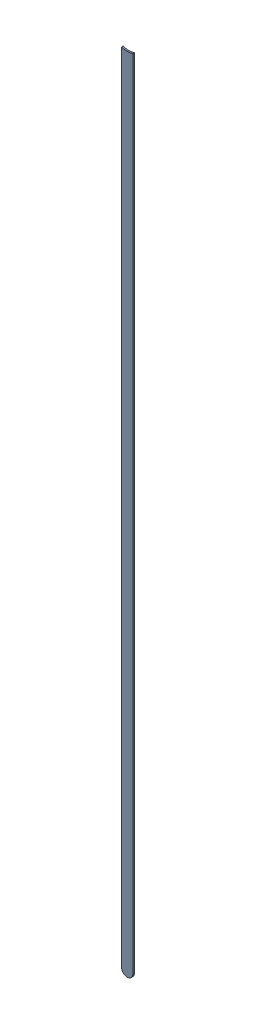
SolidWorks assembly Track (20.3mm,11.119mm)(20.3mm,29.4mm) on Bottom Layer, configuration Predeterminado. Lengths in mm.
Overall size (0.25 18.08 0.04).
2 component instances, 1 part files, 0 mates.
Components (placement in the parent):
- Track (20.3mm,11.119mm)(20.3mm,29.4mm) on Bottom Layer-1-1: Track (20.3mm,11.119mm)(20.3mm,29.4mm) on Bottom Layer-1 [Predeterminado] at (-68.317 -44.187 -0.4013) size (0.25 18.08 0.04)
  - Track (20.3mm,11.119mm)(20.3mm,29.4mm) on Bottom Layer-Part-1-1: Track (20.3mm,11.119mm)(20.3mm,29.4mm) on Bottom Layer-Part-1 [Predeterminado] at origin size (0.25 18.08 0.04)
